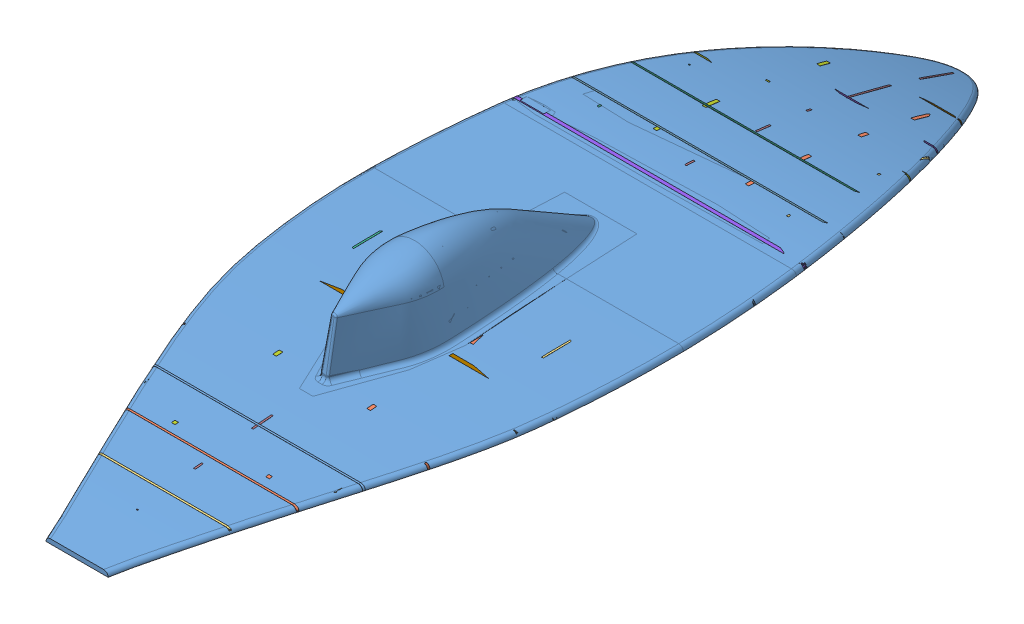
SolidWorks assembly Array Layout, configuration Default. Lengths in mm.
Overall size (2244.1 893.61 5149.59).
21 component instances, 21 part files, 64 mates.
Components (placement in the parent):
- Array Frame V2-1: Array Frame V2 [Default] at (1973.5044 2278.0681 4216.9276) size (2244.1 893.61 5149.59)
- Part2^Array Layout-1: Part2^Array Layout [Default] at (1973.5044 5406.8754 4216.9276) x (-1 0 0) z (0 -1 0) size (22.93 4512.12 270.66) (virtual)
- Part3^Array Layout-2: Part3^Array Layout [Default] at (0 5025.8754 0) x (-1 0 0) z (0 -1 0) size (12.76 3392.86 137.81) (virtual)
- Part4^Array Layout-1: Part4^Array Layout [Default] at (0 5025.8754 0) x (-1 0 0) z (0 -1 0) size (10.16 1424.94 59.48) (virtual)
- MirrorPart4^Array Layout-3: MirrorPart4^Array Layout [Default] at (6868.864 5025.8754 0) x (1 0 0) z (0 1 0) size (10.16 1424.94 59.48) (virtual)
- MirrorPart3^Array Layout-4: MirrorPart3^Array Layout [Default] at (6868.864 5025.8754 0) x (1 0 0) z (0 1 0) size (12.76 3392.86 137.81) (virtual)
- MirrorPart2^Array Layout-3: MirrorPart2^Array Layout [Default] at (4895.3596 5406.8754 4216.9276) x (1 0 0) z (0 1 0) size (22.93 4512.12 270.66) (virtual)
- Part9^Array Layout-1: Part9^Array Layout [Default] at (0 5025.8754 0) x (-1 0 0) z (0 -1 0) size (1654.54 20.33 77.9) (virtual)
- Part10^Array Layout-1: Part10^Array Layout [Default] at (0 5025.8754 0) x (-1 0 0) z (0 -1 0) size (1685.86 20.32 76.37) (virtual)
- Part11^Array Layout-1: Part11^Array Layout [Default] at (0 5025.8754 0) x (-1 0 0) z (0 -1 0) size (1724.27 10.17 52.31) (virtual)
- Part12^Array Layout-1: Part12^Array Layout [Default] at (0 5025.8754 0) x (-1 0 0) z (0 -1 0) size (1397.96 10.16 52.43) (virtual)
- Part5^Array Layout-1: Part5^Array Layout [Default] at (0 5025.8754 0) x (-1 0 0) z (0 -1 0) size (1623.76 20.32 66) (virtual)
- Part1^Array Layout-1: Part1^Array Layout [Default] at (0 5025.8754 0) x (-1 0 0) z (0 -1 0) size (10.55 4993.42 382.28) (virtual)
- Part6^Array Layout-1: Part6^Array Layout [Default] at (0 5025.8754 0) x (-1 0 0) z (0 -1 0) size (1553.22 10.16 52.29) (virtual)
- Part7^Array Layout-1: Part7^Array Layout [Default] at (0 5025.8754 0) x (-1 0 0) z (0 -1 0) size (1416.69 10.24 52.35) (virtual)
- Part8^Array Layout-1: Part8^Array Layout [Default] at (0 5025.8754 0) x (-1 0 0) z (0 -1 0) size (1239.18 10.16 52.42) (virtual)
- Part13^Array Layout-1: Part13^Array Layout [Default] at (0 5025.8754 0) x (-1 0 0) z (0 -1 0) size (1018.77 10.16 254.55) (virtual)
- Part14^Array Layout-1: Part14^Array Layout [Default] at origin size (734.38 52.67 10.16) (virtual)
- Part15^Array Layout-1: Part15^Array Layout [Default] at (0 5025.8754 0) x (-1 0 0) z (0 -1 0) size (1198 10.16 316.03) (virtual)
- Part16^Array Layout-1: Part16^Array Layout [Default] at (0 5025.8754 0) x (-1 0 0) z (0 -1 0) size (979.81 10.16 52.52) (virtual)
- Part17^Array Layout-1: Part17^Array Layout [Default] at (0 5025.8754 0) x (-1 0 0) z (0 -1 0) size (754.82 10.16 52.51) (virtual)
Mates (geometry in assembly coordinates):
- InPlace1: in place: plane of Array Frame V2-1 through (4331.3536 5406.8754 8301.6654) normal (0 -1 0); plane of ? through (0 5406.8754 0) normal (0 -1 0); moOrthogonalPlaneRef_w of Array Frame V2-1 through (4331.3536 5406.8754 8301.6654) normal (0 -1 0); plane of ? through (0 5406.8754 0) normal (0 0 -1); plane of Array Frame V2-1 through (4331.3536 5406.8754 8301.6654) normal (0 -1 0); plane of ? through (0 5406.8754 0) normal (-1 0 0); plane of Array Frame V2-1 through (4331.3536 5406.8754 8301.6654) normal (0 -1 0); unknown of Part2^Array Layout-1
- Coincident1: coincident aligned: plane of Array Frame V2-1; plane of Part2^Array Layout-1
- Coincident2: coincident aligned: moOrthogonalPlaneRef_w of Array Frame V2-1 through (1973.5044 5406.8754 4216.9276) normal (0 0 -1); plane of Part2^Array Layout-1 through (1973.5044 5406.8754 4216.9276) normal (0 0 -1)
- Coincident3: coincident anti-aligned: moOrthogonalPlaneRef_w of Array Frame V2-1 through (1973.5044 5406.8754 4216.9276) normal (1 0 0); plane of Part2^Array Layout-1 through (1973.5044 5406.8754 4216.9276) normal (-1 0 0)
- InPlace2: in place: plane of ? through (0 5025.8754 0) normal (0 -1 0); plane of ? through (0 5025.8754 0) normal (0 0 -1); plane of ? through (0 5025.8754 0) normal (-1 0 0); unknown of ?
- Coincident1: coincident aligned: 
- Coincident2: coincident aligned: plane of Part3^Array Layout-2 through (0 5025.8754 0) normal (0 0 -1)
- Coincident3: coincident anti-aligned: plane of Part3^Array Layout-2 through (0 5025.8754 0) normal (-1 0 0)
- InPlace3: in place: plane of ? through (0 5025.8754 0) normal (0 -1 0); plane of ? through (0 5025.8754 0) normal (0 0 -1); plane of ? through (0 5025.8754 0) normal (-1 0 0); unknown of ?
- Coincident4: coincident aligned: 
- Coincident5: coincident aligned: plane of Part4^Array Layout-1 through (0 5025.8754 0) normal (0 0 -1)
- Coincident6: coincident anti-aligned: plane of Part4^Array Layout-1 through (0 5025.8754 0) normal (-1 0 0)
- InPlace4: in place: plane of ? through (0 5025.8754 0) normal (0 -1 0); plane of ? through (0 5025.8754 0) normal (0 0 -1); plane of ? through (0 5025.8754 0) normal (-1 0 0); unknown of ?
- Coincident7: coincident aligned: 
- Coincident8: coincident aligned: plane of Part9^Array Layout-1 through (0 5025.8754 0) normal (0 0 -1)
- Coincident9: coincident anti-aligned: plane of Part9^Array Layout-1 through (0 5025.8754 0) normal (-1 0 0)
- InPlace5: in place: plane of ? through (0 5025.8754 0) normal (0 -1 0); plane of ? through (0 5025.8754 0) normal (0 0 -1); plane of ? through (0 5025.8754 0) normal (-1 0 0); unknown of ?
- Coincident10: coincident aligned: 
- Coincident11: coincident aligned: plane of Part10^Array Layout-1 through (0 5025.8754 0) normal (0 0 -1)
- Coincident12: coincident anti-aligned: plane of Part10^Array Layout-1 through (0 5025.8754 0) normal (-1 0 0)
- InPlace6: in place: plane of ? through (0 5025.8754 0) normal (0 -1 0); plane of ? through (0 5025.8754 0) normal (0 0 -1); plane of ? through (0 5025.8754 0) normal (-1 0 0); unknown of ?
- Coincident13: coincident aligned: 
- Coincident14: coincident aligned: plane of Part11^Array Layout-1 through (0 5025.8754 0) normal (0 0 -1)
- Coincident15: coincident anti-aligned: plane of Part11^Array Layout-1 through (0 5025.8754 0) normal (-1 0 0)
- InPlace7: in place: plane of ? through (0 5025.8754 0) normal (0 -1 0); plane of ? through (0 5025.8754 0) normal (0 0 -1); plane of ? through (0 5025.8754 0) normal (-1 0 0); unknown of ?
- Coincident16: coincident aligned: 
- Coincident17: coincident aligned: plane of Part12^Array Layout-1 through (0 5025.8754 0) normal (0 0 -1)
- Coincident18: coincident anti-aligned: plane of Part12^Array Layout-1 through (0 5025.8754 0) normal (-1 0 0)
- InPlace8: in place: plane of ? through (0 5025.8754 0) normal (0 -1 0); plane of ? through (0 5025.8754 0) normal (0 0 -1); plane of ? through (0 5025.8754 0) normal (-1 0 0); unknown of ?
- Coincident1: coincident aligned: 
- Coincident2: coincident aligned: plane of Part5^Array Layout-1 through (0 5025.8754 0) normal (0 0 -1)
- Coincident3: coincident anti-aligned: plane of Part5^Array Layout-1 through (0 5025.8754 0) normal (-1 0 0)
- InPlace9: in place: plane of ? through (0 5025.8754 0) normal (0 -1 0); plane of ? through (0 5025.8754 0) normal (0 0 -1); plane of ? through (0 5025.8754 0) normal (-1 0 0); unknown of ?
- Coincident1: coincident aligned: 
- Coincident2: coincident aligned: plane of Part1^Array Layout-1 through (0 5025.8754 0) normal (0 0 -1)
- Coincident3: coincident anti-aligned: plane of Part1^Array Layout-1 through (0 5025.8754 0) normal (-1 0 0)
- InPlace10: in place: plane of ? through (0 5025.8754 0) normal (0 -1 0); plane of ? through (0 5025.8754 0) normal (0 0 -1); plane of ? through (0 5025.8754 0) normal (-1 0 0); unknown of ?
- Coincident4: coincident aligned: 
- Coincident5: coincident aligned: plane of Part6^Array Layout-1 through (0 5025.8754 0) normal (0 0 -1)
- Coincident6: coincident anti-aligned: plane of Part6^Array Layout-1 through (0 5025.8754 0) normal (-1 0 0)
- InPlace11: in place: plane of ? through (0 5025.8754 0) normal (0 -1 0); plane of ? through (0 5025.8754 0) normal (0 0 -1); plane of ? through (0 5025.8754 0) normal (-1 0 0); unknown of ?
- Coincident7: coincident aligned: 
- Coincident8: coincident aligned: plane of Part7^Array Layout-1 through (0 5025.8754 0) normal (0 0 -1)
- Coincident9: coincident anti-aligned: plane of Part7^Array Layout-1 through (0 5025.8754 0) normal (-1 0 0)
- InPlace12: in place: plane of ? through (0 5025.8754 0) normal (0 -1 0); plane of ? through (0 5025.8754 0) normal (0 0 -1); plane of ? through (0 5025.8754 0) normal (-1 0 0); unknown of ?
- Coincident10: coincident aligned: 
- Coincident11: coincident aligned: plane of Part8^Array Layout-1 through (0 5025.8754 0) normal (0 0 -1)
- Coincident12: coincident anti-aligned: plane of Part8^Array Layout-1 through (0 5025.8754 0) normal (-1 0 0)
- InPlace13: in place: plane of ? through (0 5025.8754 0) normal (0 -1 0); plane of ? through (0 5025.8754 0) normal (0 0 -1); plane of ? through (0 5025.8754 0) normal (-1 0 0); unknown of ?
- Coincident13: coincident aligned: 
- Coincident14: coincident aligned: plane of Part13^Array Layout-1 through (0 5025.8754 0) normal (0 0 -1)
- Coincident15: coincident anti-aligned: plane of Part13^Array Layout-1 through (0 5025.8754 0) normal (-1 0 0)
- InPlace14: in place: plane of ? through (0 5025.8754 0) normal (0 -1 0); plane of ? through (0 5025.8754 0) normal (0 0 -1); plane of ? through (0 5025.8754 0) normal (-1 0 0); unknown of ?
- Coincident16: coincident aligned: 
- Coincident17: coincident aligned: plane of Part15^Array Layout-1 through (0 5025.8754 0) normal (0 0 -1)
- Coincident18: coincident anti-aligned: plane of Part15^Array Layout-1 through (0 5025.8754 0) normal (-1 0 0)
- InPlace15: in place: plane of ? through (0 5025.8754 0) normal (0 -1 0); plane of ? through (0 5025.8754 0) normal (0 0 -1); plane of ? through (0 5025.8754 0) normal (-1 0 0); unknown of ?
- Coincident1: coincident aligned: 
- Coincident2: coincident aligned: plane of Part16^Array Layout-1 through (0 5025.8754 0) normal (0 0 -1)
- Coincident3: coincident anti-aligned: plane of Part16^Array Layout-1 through (0 5025.8754 0) normal (-1 0 0)
- InPlace16: in place: plane of ? through (0 5025.8754 0) normal (0 -1 0); plane of ? through (0 5025.8754 0) normal (0 0 -1); plane of ? through (0 5025.8754 0) normal (-1 0 0); unknown of ?
- Coincident1: coincident aligned: plane of assembly through (0 5025.8754 0) normal (0 -1 0)
- Coincident2: coincident aligned: plane of Part17^Array Layout-1 through (0 5025.8754 0) normal (0 0 -1)
- Coincident3: coincident anti-aligned: plane of Part17^Array Layout-1 through (0 5025.8754 0) normal (-1 0 0)
